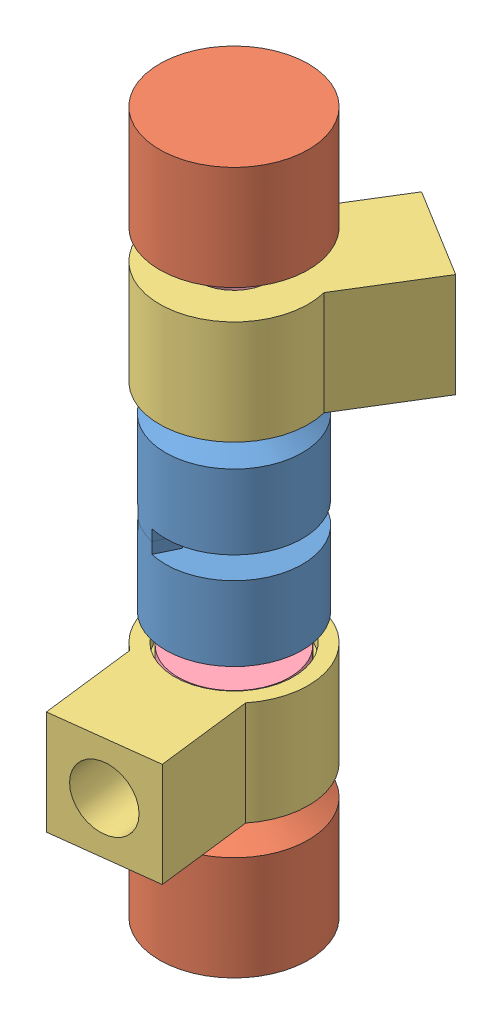
SolidWorks assembly knee_only, configuration Default. Lengths in mm.
Overall size (16.42 47.2 21.67).
9 component instances, 5 part files, 17 mates.
Components (placement in the parent):
- KneeConnectorSpringSpacer-1: KneeConnectorSpringSpacer [Default] at (5.115 -6.5699 17.4153) x (0.432628 0 -0.901572) z (0 1 0) size (9.2 9.2 7.75)
- KneeEndConnector-1: KneeEndConnector [Default] at (7.1051 -15.4199 13.2681) x (0 0 -1) z (0 -1 0) size (10 10 9)
- LegConnector1-1: LegConnector1 [Default] at (7.1051 -13.4199 13.2681) x (0.992677 0 -0.120796) z (0.120796 0 0.992677) size (10 7 15)
- bushing-1: bushing [Default] at (7.1051 -7.3199 13.2681) size (7.5 5 7.5)
- ScrewThread-1: ScrewThread [Default] at (7.1051 -20.4199 13.2681) size (3 43 3)
- LegConnector1-2: LegConnector1 [Default] at (7.1051 15.7801 13.2681) x (0.851559 0 0.524259) z (0.524259 0 -0.851559) size (10 7 15)
- KneeConnectorSpringSpacer-2: KneeConnectorSpringSpacer [Default] at (5.115 8.9301 17.4153) x (0.432628 0 -0.901572) z (0 -1 0) size (9.2 9.2 7.75)
- KneeEndConnector-2: KneeEndConnector [Default] at (7.1051 17.7801 13.2681) x (0.546944 0 -0.837169) z (0 1 0) size (10 10 9)
- bushing-2: bushing [Default] at (7.1051 9.6801 13.2681) x (0.837169 0 0.546944) z (0.546944 0 -0.837169) size (7.5 5 7.5)
Mates (geometry in assembly coordinates):
- Concentric1: concentric anti-aligned: cylinder of LegConnector1-1 through (7.1051 -6.4199 13.2681) axis (0 -1 0) radius 2.4; cylinder of bushing-1 through (7.1051 -11.5699 13.2681) axis (0 1 0) radius 2.25
- Coincident1: coincident anti-aligned: plane of LegConnector1-1 through (7.1051 -7.3199 13.2681) normal (0 1 0); plane of bushing-1 through (7.1051 -7.3199 13.2681) normal (0 -1 0)
- Concentric2: concentric anti-aligned: cylinder of KneeEndConnector-1 through (7.1051 -15.4199 13.2681) axis (0 1 0) radius 1.55; cylinder of bushing-1 through (7.1051 -6.5699 13.2681) axis (0 -1 0) radius 1.5
- Coincident2: coincident anti-aligned: circle of KneeEndConnector-1; plane of LegConnector1-1 through (7.1051 -13.4199 13.2681) normal (0 -1 0)
- Concentric4: concentric anti-aligned: cylinder of KneeConnectorSpringSpacer-1 through (7.1051 -6.5699 13.2681) axis (0 1 0) radius 1.55; cylinder of bushing-1 through (7.1051 -6.5699 13.2681) axis (0 -1 0) radius 1.5
- Coincident3: coincident aligned: circle of KneeConnectorSpringSpacer-1; plane of bushing-1 through (7.1051 -6.5699 13.2681) normal (0 1 0)
- Concentric6: concentric anti-aligned: cylinder of LegConnector1-2 through (7.1051 8.7801 13.2681) axis (0 1 0) radius 2.4; cylinder of bushing-2 through (7.1051 13.9301 13.2681) axis (0 -1 0) radius 2.25
- Coincident4: coincident anti-aligned: plane of LegConnector1-2 through (7.1051 15.7801 13.2681) normal (0 1 0); circle of KneeEndConnector-2
- Coincident5: coincident anti-aligned: plane of LegConnector1-2 through (7.1051 9.6801 13.2681) normal (0 -1 0); plane of bushing-2 through (7.1051 9.6801 13.2681) normal (0 1 0)
- Coincident6: coincident aligned: circle of KneeConnectorSpringSpacer-2; plane of bushing-2 through (7.1051 8.9301 13.2681) normal (0 -1 0)
- Concentric7: concentric anti-aligned: cylinder of KneeConnectorSpringSpacer-2 through (7.1051 8.9301 13.2681) axis (0 -1 0) radius 1.55; cylinder of bushing-2 through (7.1051 8.9301 13.2681) axis (0 1 0) radius 1.5
- Concentric8: concentric anti-aligned: cylinder of KneeEndConnector-2 through (7.1051 17.7801 13.2681) axis (0 -1 0) radius 1.55; cylinder of bushing-2 through (7.1051 8.9301 13.2681) axis (0 1 0) radius 1.5
- Coincident7: coincident anti-aligned: plane of KneeEndConnector-1 through (7.1051 -20.4199 13.2681) normal (0 1 0); plane of ScrewThread-1 through (7.1051 -20.4199 13.2681) normal (0 -1 0)
- Concentric9: concentric anti-aligned: cylinder of KneeConnectorSpringSpacer-1 through (7.1051 -6.5699 13.2681) axis (0 1 0) radius 1.55; cylinder of ScrewThread-1 through (7.1051 22.5801 13.2681) axis (0 -1 0) radius 1.5
- Concentric10: concentric aligned: cylinder of ScrewThread-1 through (7.1051 22.5801 13.2681) axis (0 -1 0) radius 1.5; cylinder of KneeConnectorSpringSpacer-2 through (7.1051 8.9301 13.2681) axis (0 -1 0) radius 1.55
- Coincident9: coincident anti-aligned: plane of KneeConnectorSpringSpacer-1 through (7.1051 1.1801 13.2681) normal (0 1 0); plane of KneeConnectorSpringSpacer-2 through (7.1051 1.1801 13.2681) normal (0 -1 0)
- Parallel3: parallel anti-aligned: line of KneeConnectorSpringSpacer-1 through (4.9327 1.1801 15.4837) axis (-0.432628 0 0.901572); line of KneeConnectorSpringSpacer-2 through (4.261 1.1801 16.8835) axis (0.432628 0 -0.901572)
